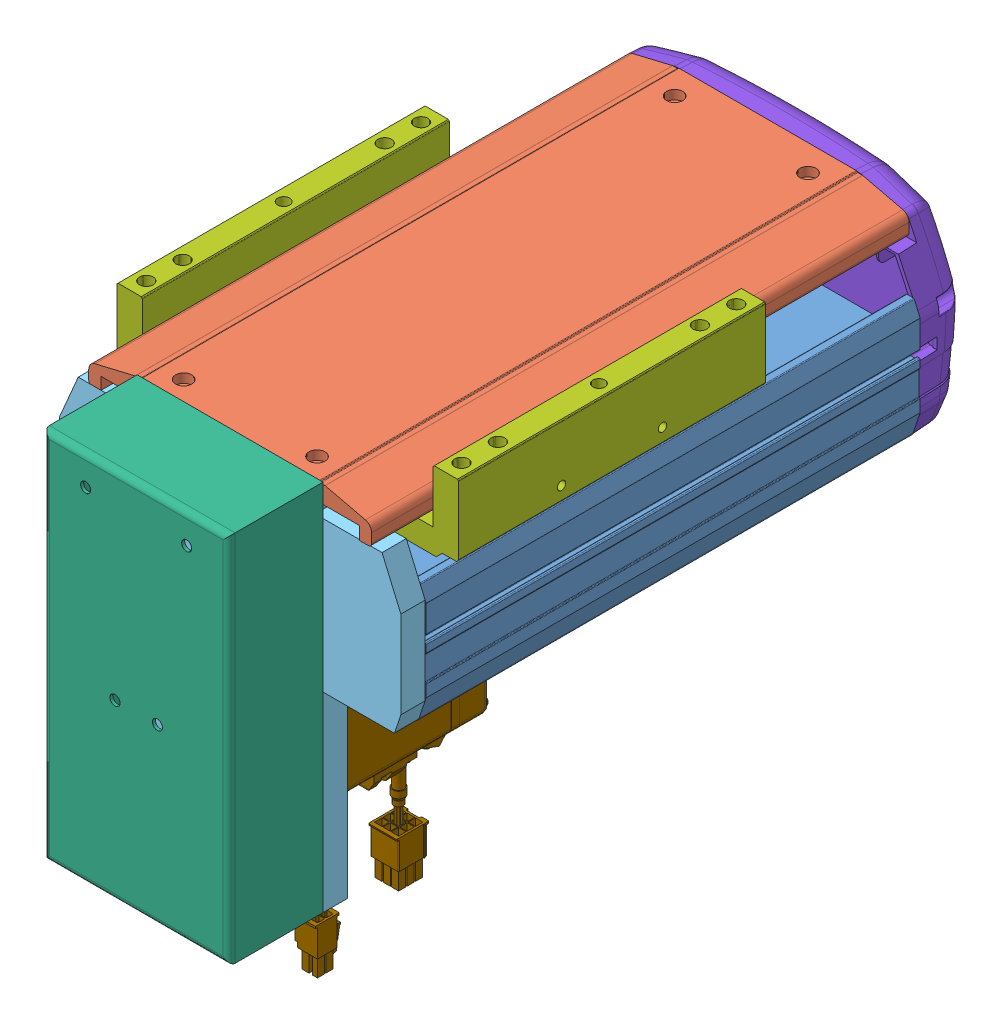
SolidWorks assembly S17-BM-400W, configuration 默认. Lengths in mm.
Overall size (183.77 261.45 333.22).
12 component instances, 10 part files, 39 mates.
Components (placement in the parent):
- S17-BM底座^S17-BM-400W-1: S17-BM底座^S17-BM-400W [默认] at origin size (170 59.5 261.5) (virtual)
- S17-BM上盖^S17-BM-400W-2: S17-BM上盖^S17-BM-400W [默认] at (0 90.5 7.5) size (140 15.5 266) (virtual)
- EE-SX672 传感器^S17-BM-400W-1: EE-SX672 传感器^S17-BM-400W [默认] at (-91.7485 41.1 153.8) x (-1 0 0) z (0 0 1) size (13.5 27.4 26.1) (virtual)
- EE-SX672 传感器^S17-BM-400W-2: EE-SX672 传感器^S17-BM-400W [默认] at (-91.7485 41.1 179.9) x (-1 0 0) z (0 0 1) size (13.5 27.4 26.1) (virtual)
- EE-SX672 传感器^S17-BM-400W-3: EE-SX672 传感器^S17-BM-400W [默认] at (-91.7485 41.1 106) x (-1 0 0) z (0 0 1) size (13.5 27.4 26.1) (virtual)
- S17-BM 感应片(外置)^S17-BM-400W-1: S17-BM 感应片(外置)^S17-BM-400W [默认] at (-84.5 76 134) x (-1 0 0) z (0 0 -1) size (8 30 70) (virtual)
- S17-BM-P75电机安装板下折750W^S17-BM-400W-1: S17-BM-P75电机安装板下折750W^S17-BM-400W [默认] at (-0.0017 50 273.5) x (-1 0 0) z (0 0 -1) size (169 176 12) (virtual)
- S17-BM盖子^S17-BM-400W-1: S17-BM盖子^S17-BM-400W [默认] at (-0.0017 -1.25 320.5) x (-1 0 0) z (0 0 -1) size (92 184.5 46.5) (virtual)
- S17-BC丝杆螺母连接座^S17-BM-400W-1: S17-BC丝杆螺母连接座^S17-BM-400W [Default] at (0 97 169) size (169 71 152) (virtual)
- 复件 S17塑胶端盖^S17-BM-400W-4: 复件 S17塑胶端盖^S17-BM-400W [Default] at (0 -0.0852 -13) x (-1 0 0) z (0 0 -1) size (170.72 91.84 30.22) (virtual)
- 复件 松下400W电机MHMF042L1U22^S17-BM-400W-1: 复件 松下400W电机MHMF042L1U22^S17-BM-400W [默认] at (-0.0015 -45.25 261.5) x (0 0 1) z (1 0 0) size (118 149.2 60) (virtual)
- 复件 304电机调整外固定片^S17-BM-400W-1: 复件 304电机调整外固定片^S17-BM-400W [Default] at (170.3975 -93.5 192.241) x (-1 0 0) z (0 -1 0) size (25 35 3) (virtual)
Mates (geometry in assembly coordinates):
- 距离10: distance = 97 mm: plane of S17-BC丝杆螺母连接座^S17-BM-400W-1 through (72.5 97 245) normal (0 1 0); plane of S17-BM底座^S17-BM-400W-1 through (0 0 261.5) normal (0 -1 0)
- 距离11: distance = 90.5 mm: plane of S17-BM上盖^S17-BM-400W-2 through (-43.7927 90.5 273.5) normal (0 1 0); plane of S17-BM底座^S17-BM-400W-1 through (0 0 261.5) normal (0 -1 0)
- 重合153: coincident: plane of S17-BM底座^S17-BM-400W-1 through (0 0 0) normal (1 0 0); plane of S17-BM上盖^S17-BM-400W-2 through (0 90.5 7.5) normal (1 0 0)
- 重合156: coincident: plane of S17-BM底座^S17-BM-400W-1 through (0 0 0) normal (1 0 0); plane of S17-BC丝杆螺母连接座^S17-BM-400W-1 through (0 97 169) normal (1 0 0)
- 重合157: coincident: plane of EE-SX672 传感器^S17-BM-400W-1 through (-84.9985 52.2 160.1) normal (1 0 0); plane of EE-SX672 传感器^S17-BM-400W-3 through (-84.9985 52.2 112.3) normal (1 0 0)
- 重合158: coincident: plane of EE-SX672 传感器^S17-BM-400W-1 through (-84.9985 52.2 160.1) normal (1 0 0); plane of EE-SX672 传感器^S17-BM-400W-2 through (-84.9985 52.2 186.2) normal (1 0 0)
- 重合159: coincident: plane of EE-SX672 传感器^S17-BM-400W-1 through (-84.9985 52.2 160.1) normal (0 1 0); plane of EE-SX672 传感器^S17-BM-400W-3 through (-84.9985 52.2 112.3) normal (0 1 0)
- 重合160: coincident: plane of EE-SX672 传感器^S17-BM-400W-1 through (-84.9985 52.2 160.1) normal (0 1 0); plane of EE-SX672 传感器^S17-BM-400W-2 through (-84.9985 52.2 186.2) normal (0 1 0)
- 距离20: distance = 30 mm: plane of S17-BM底座^S17-BM-400W-1 through (0 0 261.5) normal (0 -1 0); plane of EE-SX672 传感器^S17-BM-400W-2 through (-84.9985 30 186.2) normal (0 -1 0)
- 同心109: concentric: cylinder of S17-BM 感应片(外置)^S17-BM-400W-1 through (-84.5 69 194) axis (1 0 0) radius 2.8; cylinder of S17-BC丝杆螺母连接座^S17-BM-400W-1 through (-84.5 69 194) axis (-1 0 0) radius 2.1
- 同心111: concentric: cylinder of S17-BM 感应片(外置)^S17-BM-400W-1 through (-84.5 69 144) axis (1 0 0) radius 2.8; cylinder of S17-BC丝杆螺母连接座^S17-BM-400W-1 through (-84.5 69 144) axis (-1 0 0) radius 2.1
- 重合163: coincident: plane of S17-BC丝杆螺母连接座^S17-BM-400W-1 through (-84.5 62.7074 245) normal (-1 0 0); plane of S17-BM 感应片(外置)^S17-BM-400W-1 through (-84.5 76 134) normal (1 0 0)
- 重合168: coincident: plane of S17-BM底座^S17-BM-400W-1 through (-84.9985 0 261.5) normal (-1 0 0); plane of EE-SX672 传感器^S17-BM-400W-2 through (-84.9985 52.2 186.2) normal (1 0 0)
- 重合169: coincident: plane of EE-SX672 传感器^S17-BM-400W-1 through (-87.9985 33.2 170) normal (0 0 1); plane of EE-SX672 传感器^S17-BM-400W-2 through (-87.9985 33.2 170) normal (0 0 -1)
- 距离23: distance = 1 mm: plane of S17-BM底座^S17-BM-400W-1 through (0 0 261.5) normal (0 -1 0); plane of S17-BM-P75电机安装板下折750W^S17-BM-400W-1 through (-0.0017 1 261.5) normal (0 -1 0)
- 重合172: coincident: plane of S17-BM底座^S17-BM-400W-1 through (-84.4985 0 261.5) normal (-1 0 0); plane of S17-BM-P75电机安装板下折750W^S17-BM-400W-1 through (-84.4985 50 261.5) normal (-1 0 0)
- 重合174: coincident: plane of S17-BM底座^S17-BM-400W-1 through (0 0 261.5) normal (0 0 1); plane of S17-BM-P75电机安装板下折750W^S17-BM-400W-1 through (-0.0017 50 261.5) normal (0 0 -1)
- 重合180: coincident: plane of S17-BM-P75电机安装板下折750W^S17-BM-400W-1 through (-0.0017 50 273.5) normal (0 0 1); plane of S17-BM盖子^S17-BM-400W-1 through (45.9983 -93.5 273.5) normal (0 0 -1)
- 重合181: coincident: plane of S17-BM-P75电机安装板下折750W^S17-BM-400W-1 through (-0.0017 -93.5 261.5) normal (0 -1 0); plane of S17-BM盖子^S17-BM-400W-1 through (45.9983 -93.5 273.5) normal (0 -1 0)
- 重合182: coincident: plane of S17-BM-P75电机安装板下折750W^S17-BM-400W-1 through (45.9983 50 261.5) normal (1 0 0); plane of S17-BM盖子^S17-BM-400W-1 through (45.9983 91 273.5) normal (1 0 0)
- 重合183: coincident: plane of S17-BM底座^S17-BM-400W-1 through (0 0 0) normal (0 0 1); plane of assembly through (0 0 0) normal (0 0 1)
- 重合184: coincident: plane of S17-BM底座^S17-BM-400W-1 through (0 0 0) normal (0 1 0); plane of assembly through (0 0 0) normal (0 1 0)
- 重合186: coincident: plane of S17-BM底座^S17-BM-400W-1 through (0 0 0) normal (1 0 0); plane of assembly through (0 0 0) normal (1 0 0)
- 重合187: coincident: plane of S17-BM上盖^S17-BM-400W-2 through (68.2998 76.7 273.5) normal (0 0 1); plane of S17-BM盖子^S17-BM-400W-1 through (45.9983 -93.5 273.5) normal (0 0 -1)
- 重合202: coincident: plane of S17-BM底座^S17-BM-400W-1 through (96.5232 59.4999 17) normal (0 0 -1); plane of 复件 S17塑胶端盖^S17-BM-400W-4 through (0 -0.0852 17) normal (0 0 1)
- 重合203: coincident: line of S17-BM上盖^S17-BM-400W-2 through (43.7927 90.5 7.5) axis (-1 0 0); line of 复件 S17塑胶端盖^S17-BM-400W-4 through (43.4408 90.5 7.5) axis (-1 0 0)
- 重合204: coincident: line of S17-BM底座^S17-BM-400W-1 through (79.4985 35.3956 17) axis (0 1 0); plane of 复件 S17塑胶端盖^S17-BM-400W-4 through (79.4985 35.0648 17) normal (1 0 0)
- 重合205: coincident: plane of S17-BM-P75电机安装板下折750W^S17-BM-400W-1 through (-0.0017 50 261.5) normal (0 0 -1); plane of 复件 松下400W电机MHMF042L1U22^S17-BM-400W-1 through (24.9985 -70.25 261.5) normal (0 0 1)
- 平行2: parallel: line of S17-BM盖子^S17-BM-400W-1 through (45.9983 -93.5 273.5) axis (-1 0 0); plane of 复件 松下400W电机MHMF042L1U22^S17-BM-400W-1 through (-25.0015 -75.25 190) normal (0 -1 0)
- 同心112: concentric: cylinder of S17-BM-P75电机安装板下折750W^S17-BM-400W-1 through (-0.0017 -45.25 273.5) axis (0 0 -1) radius 12.5; cylinder of 复件 松下400W电机MHMF042L1U22^S17-BM-400W-1 through (-0.0017 -45.25 291.5) axis (0 0 -1) radius 7
- 距离24: distance = 138 mm: plane of EE-SX672 传感器^S17-BM-400W-2 through (-98.4985 30 186.2) normal (0 0 1); plane of S17-BM盖子^S17-BM-400W-1 through (45.9983 -93.5 320) normal (0 0 1)
- 距离25: distance = 89 mm: plane of EE-SX672 传感器^S17-BM-400W-3 through (-98.4985 30 106) normal (0 0 -1); plane of 复件 S17塑胶端盖^S17-BM-400W-4 through (0 -0.0852 17) normal (0 0 1)
- 宽度1: width: plane of S17-BM 感应片(外置)^S17-BM-400W-1 through (-85.3 63 162.5) normal (0 0 -1); plane of S17-BM 感应片(外置)^S17-BM-400W-1 through (-85.3 46 177.5) normal (0 0 1); plane of EE-SX672 传感器^S17-BM-400W-1 through (-98.4985 30 160.1) normal (0 0 1); plane of EE-SX672 传感器^S17-BM-400W-2 through (-98.4985 30 179.9) normal (0 0 -1)
- 重合210: coincident: plane of S17-BM-P75电机安装板下折750W^S17-BM-400W-1 through (-0.0017 -93.5 261.5) normal (0 -1 0); plane of 复件 304电机调整外固定片^S17-BM-400W-1 through (170.3975 -93.5 192.241) normal (0 1 0)
- 宽度3: width: plane of S17-BM盖子^S17-BM-400W-1 through (45.9983 91 273.5) normal (1 0 0); plane of S17-BM盖子^S17-BM-400W-1 through (-46.0017 91 273.5) normal (-1 0 0); plane of 复件 304电机调整外固定片^S17-BM-400W-1 through (-12.5017 -96.5 261.5) normal (-1 0 0); plane of 复件 304电机调整外固定片^S17-BM-400W-1 through (12.4983 -96.5 261.5) normal (1 0 0)
- 重合211: coincident: plane of S17-BM-P75电机安装板下折750W^S17-BM-400W-1 through (-0.0017 50 261.5) normal (0 0 -1); plane of 复件 304电机调整外固定片^S17-BM-400W-1 through (12.4983 -96.5 261.5) normal (0 0 -1)
- 距离26: distance = 45.25 mm: cylinder of 复件 松下400W电机MHMF042L1U22^S17-BM-400W-1 through (-0.0015 -45.25 291.5) axis (0 0 -1) radius 7; plane of S17-BM底座^S17-BM-400W-1 through (0 0 261.5) normal (0 -1 0)
- 距离28: distance = 85 mm: cylinder of 复件 松下400W电机MHMF042L1U22^S17-BM-400W-1 through (-0.0015 -45.25 291.5) axis (0 0 -1) radius 7; plane of S17-BM底座^S17-BM-400W-1 through (84.9985 0 261.5) normal (1 0 0)
- 距离29: distance = 151 mm: cylinder of S17-BC丝杆螺母连接座^S17-BM-400W-1 through (78 97 169) axis (0 1 0) radius 3; plane of S17-BM盖子^S17-BM-400W-1 through (45.9983 -93.5 320) normal (0 0 1)
